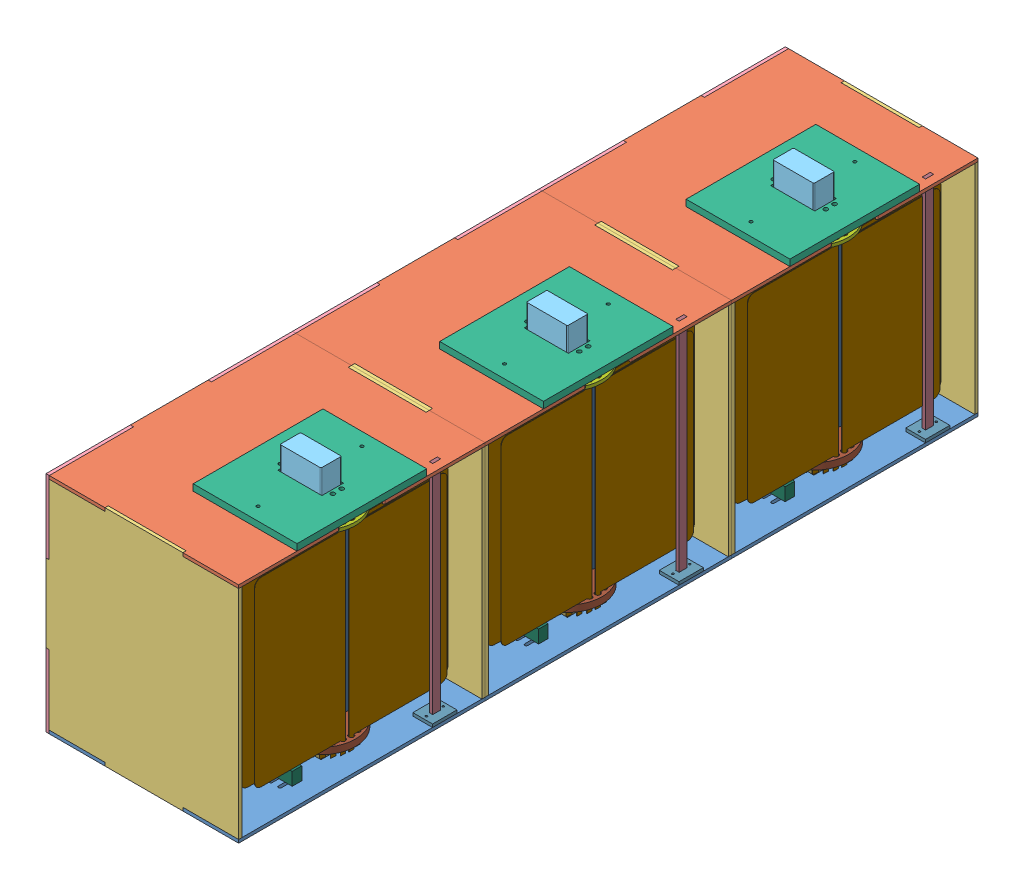
SolidWorks assembly AllAssembly-v1-stacked, configuration Default. Lengths in mm.
Overall size (189.19 247.83 723.9).
132 component instances, 15 part files, 6 mates.
Components (placement in the parent):
- BasicFlipbook-1: BasicFlipbook [Default] at (-56.8677 536.304 -217.1524) size (189.19 247.83 241.3)
  - sidePanel-bearing-1: sidePanel-bearing [Default] at (77.8088 -538.0926 524.9276) size (188.59 3.17 241.3)
  - sidePanel-spindle-1: sidePanel-spindle [Default] at (77.8088 -322.1926 524.9276) size (188.59 3.17 241.3)
  - topPanel-1: topPanel [Default] at (170.5188 -428.5551 283.6276) x (0 -1 0) z (0 0 1) size (219.07 188.59 3.17)
  - topPanel-2: topPanel [Default] at (170.5188 -428.5551 521.7526) x (0 -1 0) z (0 0 1) size (219.07 188.59 3.17)
  - backPanel-1: backPanel [Default] at (77.8088 -538.0926 524.9276) x (0 1 0) z (0 0 1) size (219.07 3.17 241.3)
  - servo-1: servo [Default] at (213.1908 -290.2676 404.2776) x (1 0 0) z (0 -1 0) size (52.83 20.07 43.1)
  - sidePanel-motor-1: sidePanel-motor [Default] at (77.8088 -319.0176 524.9276) size (101.6 6.35 127)
  - FlipHubAssy_11_14_16-2: FlipHubAssy_11_14_16 [Default] at (223.2238 -424.2676 404.2776) x (0 1 0) z (0.343761 0 0.939057) size (212.25 171.9 216.35) (flexible)
    - Hub_11_16_16v1-3: Hub_11_16_16v1 [Kerf Removed] at (92.075 0 0) x (0 -0.836215 0.548402) z (1 0 0) size (67.6 67.6 3.17)
    - 4mmShaft-1: 4mmShaft [Default] at (-110.65 0 0) x (0 0.397838 0.917456) z (1 0 0) size (4 4 201.85)
    - flipcard-2: flipcard [Default] at (101.6 -15.2897 -21.654) x (-1 0 0) z (0 0.118273 0.992981) size (203.2 0.36 88.9)
    - flipcard-3: flipcard [Default] at (101.6 -20.7049 -16.8264) x (-1 0 0) z (0 0.229727 0.973255) size (203.2 0.36 88.9)
    - flipcard-4: flipcard [Default] at (101.6 -24.7798 -10.679) x (-1 0 0) z (0 0.290896 0.956755) size (203.2 0.36 88.9)
    - flipcard-5: flipcard [Default] at (101.6 -27.1726 -3.6323) x (-1 0 0) z (0 0.324243 0.945974) size (203.2 0.36 88.9)
    - flipcard-6: flipcard [Default] at (101.6 -27.6554 3.8125) x (-1 0 0) z (0 0.355007 0.934864) size (203.2 0.36 88.9)
    - flipcard-7: flipcard [Default] at (101.6 6.9617 25.991) x (-1 0 0) z (0 -0.804275 -0.594258) size (203.2 0.36 88.9)
    - flipcard-8: flipcard [Default] at (101.6 13.6608 22.8217) x (-1 0 0) z (0 -0.829103 -0.559096) size (203.2 0.36 88.9)
    - flipcard-9: flipcard [Default] at (101.6 12.4258 -23.2935) x (-1 0 0) z (0 -0.27854 0.960425) size (203.2 0.36 88.9)
    - flipcard-10: flipcard [Default] at (101.6 19.1668 18.301) x (-1 0 0) z (0 -0.912348 -0.409415) size (203.2 0.36 88.9)
    - flipcard-11: flipcard [Default] at (101.6 25.8239 6.5692) x (-1 0 0) z (0 -0.973268 0.229671) size (203.2 0.36 88.9)
    - flipcard-12: flipcard [Default] at (101.6 -7.402 26.2839) x (-1 0 0) z (0 -0.588891 -0.808212) size (203.2 0.36 88.9)
    - flipcard-13: flipcard [Default] at (101.6 23.2571 13.1974) x (-1 0 0) z (0 -0.999195 0.040112) size (203.2 0.36 88.9)
    - flipcard-14: flipcard [Default] at (101.6 -0.029 26.9321) x (-1 0 0) z (0 -0.634806 -0.772672) size (203.2 0.36 88.9)
    - flipcard-15: flipcard [Default] at (101.6 -14.3329 23.6973) x (-1 0 0) z (0 -0.524162 -0.851618) size (203.2 0.36 88.9)
    - flipcard-16: flipcard [Default] at (101.6 25.5857 -7.2828) x (-1 0 0) z (0 -0.75236 0.658752) size (203.2 0.36 88.9)
    - flipcard-17: flipcard [Default] at (101.6 -20.2143 19.2851) x (-1 0 0) z (0 -0.387069 -0.922051) size (203.2 0.36 88.9)
    - flipcard-18: flipcard [Default] at (101.6 -26.2822 11.1902) x (-1 0 0) z (0 0.343761 0.939057) size (203.2 0.36 88.9)
    - flipcard-19: flipcard [Default] at (101.6 26.6468 -0.3343) x (-1 0 0) z (0 -0.879712 0.475507) size (203.2 0.36 88.9)
    - flipcard-20: flipcard [Default] at (101.6 -25.0081 13.5575) x (-1 0 0) z (0 -0.343761 -0.939057) size (203.2 0.36 88.9)
    - flipcard-21: flipcard [Default] at (101.6 22.7931 -13.6775) x (-1 0 0) z (0 -0.570443 0.821337) size (203.2 0.36 88.9)
    - flipcard-22: flipcard [Default] at (101.6 5.6236 -25.7226) x (-1 0 0) z (0 -0.165302 0.986243) size (203.2 0.36 88.9)
    - flipcard-23: flipcard [Default] at (101.6 -1.5593 -26.2681) x (-1 0 0) z (0 -0.043757 0.999042) size (203.2 0.36 88.9)
    - flipcard-24: flipcard [Default] at (101.6 18.5239 -19.098) x (-1 0 0) z (0 -0.319136 0.947709) size (203.2 0.36 88.9)
    - flipcard-26: flipcard [Default] at (101.6 -8.628 -24.8962) x (-1 0 0) z (0 0.08016 0.996782) size (203.2 0.36 88.9)
    - CenterSupport-2: CenterSupport [After Cut Kerf Removed] at (0 3.7916 3.0025) x (1 0 0) z (0 -0.836215 0.548402) size (190.5 19.05 3.05)
    - CenterSupport-3: CenterSupport [After Cut Kerf Removed] at (0 -3.0025 3.7916) x (1 0 0) z (0 -0.548402 -0.836215) size (190.5 19.05 3.05)
    - CenterSupport-4: CenterSupport [After Cut Kerf Removed] at (0 -3.7916 -3.0025) x (1 0 0) z (0 0.836215 -0.548402) size (190.5 19.05 3.05)
    - CenterSupport-5: CenterSupport [After Cut Kerf Removed] at (0 3.0025 -3.7916) x (1 0 0) z (0 0.548402 0.836215) size (190.5 19.05 3.05)
    - Hub_11_16_16v1-thicker-3: Hub_11_16_16v1-thicker [Kerf Removed] at (-95.25 0 0) x (0 -0.548402 -0.836215) z (1 0 0) size (67.6 72.68 6.35)
    - bearingSleeve-nut-1: bearingSleeve-nut [Default] at (-109.05 0 0) x (0 -0.939057 0.343761) z (-1 0 0) size (25.4 25.4 6.95)
  - stopper-2: stopper [Default] at (255.3548 -538.0926 327.0616) x (0 1 0) z (-1 0 0) size (219.07 7.87 3.3)
  - stopperSupport-1: stopperSupport [Default] at (243.9268 -531.9176 311.1876) x (1 0 0) z (0 -1 0) size (19.3 23.87 3)
  - switchSupport-1: switchSupport [Default] at (224.5478 -534.9176 453.6616) x (1 0 0) z (0 1 0) size (19.84 9.4 12.7)
- BasicFlipbook-2: BasicFlipbook [Default] at (-56.8677 536.304 -458.4524) size (189.19 247.83 241.3)
  - sidePanel-bearing-1: sidePanel-bearing [Default] at (77.8088 -538.0926 524.9276) size (188.59 3.17 241.3)
  - sidePanel-spindle-1: sidePanel-spindle [Default] at (77.8088 -322.1926 524.9276) size (188.59 3.17 241.3)
  - topPanel-1: topPanel [Default] at (170.5188 -428.5551 283.6276) x (0 -1 0) z (0 0 1) size (219.07 188.59 3.17)
  - topPanel-2: topPanel [Default] at (170.5188 -428.5551 521.7526) x (0 -1 0) z (0 0 1) size (219.07 188.59 3.17)
  - backPanel-1: backPanel [Default] at (77.8088 -538.0926 524.9276) x (0 1 0) z (0 0 1) size (219.07 3.17 241.3)
  - servo-1: servo [Default] at (213.1908 -290.2676 404.2776) x (1 0 0) z (0 -1 0) size (52.83 20.07 43.1)
  - sidePanel-motor-1: sidePanel-motor [Default] at (77.8088 -319.0176 524.9276) size (101.6 6.35 127)
  - FlipHubAssy_11_14_16-2: FlipHubAssy_11_14_16 [Default] at (223.2238 -424.2676 404.2776) x (0 1 0) z (0.343761 0 0.939057) size (212.25 171.9 216.35) (flexible)
    - Hub_11_16_16v1-3: Hub_11_16_16v1 [Kerf Removed] at (92.075 0 0) x (0 -0.836215 0.548402) z (1 0 0) size (67.6 67.6 3.17)
    - 4mmShaft-1: 4mmShaft [Default] at (-110.65 0 0) x (0 0.397838 0.917456) z (1 0 0) size (4 4 201.85)
    - flipcard-2: flipcard [Default] at (101.6 -15.2897 -21.654) x (-1 0 0) z (0 0.118273 0.992981) size (203.2 0.36 88.9)
    - flipcard-3: flipcard [Default] at (101.6 -20.7049 -16.8264) x (-1 0 0) z (0 0.229727 0.973255) size (203.2 0.36 88.9)
    - flipcard-4: flipcard [Default] at (101.6 -24.7798 -10.679) x (-1 0 0) z (0 0.290896 0.956755) size (203.2 0.36 88.9)
    - flipcard-5: flipcard [Default] at (101.6 -27.1726 -3.6323) x (-1 0 0) z (0 0.324243 0.945974) size (203.2 0.36 88.9)
    - flipcard-6: flipcard [Default] at (101.6 -27.6554 3.8125) x (-1 0 0) z (0 0.355007 0.934864) size (203.2 0.36 88.9)
    - flipcard-7: flipcard [Default] at (101.6 6.9617 25.991) x (-1 0 0) z (0 -0.804275 -0.594258) size (203.2 0.36 88.9)
    - flipcard-8: flipcard [Default] at (101.6 13.6608 22.8217) x (-1 0 0) z (0 -0.829103 -0.559096) size (203.2 0.36 88.9)
    - flipcard-9: flipcard [Default] at (101.6 12.4258 -23.2935) x (-1 0 0) z (0 -0.27854 0.960425) size (203.2 0.36 88.9)
    - flipcard-10: flipcard [Default] at (101.6 19.1668 18.301) x (-1 0 0) z (0 -0.912348 -0.409415) size (203.2 0.36 88.9)
    - flipcard-11: flipcard [Default] at (101.6 25.8239 6.5692) x (-1 0 0) z (0 -0.973268 0.229671) size (203.2 0.36 88.9)
    - flipcard-12: flipcard [Default] at (101.6 -7.402 26.2839) x (-1 0 0) z (0 -0.588891 -0.808212) size (203.2 0.36 88.9)
    - flipcard-13: flipcard [Default] at (101.6 23.2571 13.1974) x (-1 0 0) z (0 -0.999195 0.040112) size (203.2 0.36 88.9)
    - flipcard-14: flipcard [Default] at (101.6 -0.029 26.9321) x (-1 0 0) z (0 -0.634806 -0.772672) size (203.2 0.36 88.9)
    - flipcard-15: flipcard [Default] at (101.6 -14.3329 23.6973) x (-1 0 0) z (0 -0.524162 -0.851618) size (203.2 0.36 88.9)
    - flipcard-16: flipcard [Default] at (101.6 25.5857 -7.2828) x (-1 0 0) z (0 -0.75236 0.658752) size (203.2 0.36 88.9)
    - flipcard-17: flipcard [Default] at (101.6 -20.2143 19.2851) x (-1 0 0) z (0 -0.387069 -0.922051) size (203.2 0.36 88.9)
    - flipcard-18: flipcard [Default] at (101.6 -26.2822 11.1902) x (-1 0 0) z (0 0.343761 0.939057) size (203.2 0.36 88.9)
    - flipcard-19: flipcard [Default] at (101.6 26.6468 -0.3343) x (-1 0 0) z (0 -0.879712 0.475507) size (203.2 0.36 88.9)
    - flipcard-20: flipcard [Default] at (101.6 -25.0081 13.5575) x (-1 0 0) z (0 -0.343761 -0.939057) size (203.2 0.36 88.9)
    - flipcard-21: flipcard [Default] at (101.6 22.7931 -13.6775) x (-1 0 0) z (0 -0.570443 0.821337) size (203.2 0.36 88.9)
    - flipcard-22: flipcard [Default] at (101.6 5.6236 -25.7226) x (-1 0 0) z (0 -0.165302 0.986243) size (203.2 0.36 88.9)
    - flipcard-23: flipcard [Default] at (101.6 -1.5593 -26.2681) x (-1 0 0) z (0 -0.043757 0.999042) size (203.2 0.36 88.9)
    - flipcard-24: flipcard [Default] at (101.6 18.5239 -19.098) x (-1 0 0) z (0 -0.319136 0.947709) size (203.2 0.36 88.9)
    - flipcard-26: flipcard [Default] at (101.6 -8.628 -24.8962) x (-1 0 0) z (0 0.08016 0.996782) size (203.2 0.36 88.9)
    - CenterSupport-2: CenterSupport [After Cut Kerf Removed] at (0 3.7916 3.0025) x (1 0 0) z (0 -0.836215 0.548402) size (190.5 19.05 3.05)
    - CenterSupport-3: CenterSupport [After Cut Kerf Removed] at (0 -3.0025 3.7916) x (1 0 0) z (0 -0.548402 -0.836215) size (190.5 19.05 3.05)
    - CenterSupport-4: CenterSupport [After Cut Kerf Removed] at (0 -3.7916 -3.0025) x (1 0 0) z (0 0.836215 -0.548402) size (190.5 19.05 3.05)
    - CenterSupport-5: CenterSupport [After Cut Kerf Removed] at (0 3.0025 -3.7916) x (1 0 0) z (0 0.548402 0.836215) size (190.5 19.05 3.05)
    - Hub_11_16_16v1-thicker-3: Hub_11_16_16v1-thicker [Kerf Removed] at (-95.25 0 0) x (0 -0.548402 -0.836215) z (1 0 0) size (67.6 72.68 6.35)
    - bearingSleeve-nut-1: bearingSleeve-nut [Default] at (-109.05 0 0) x (0 -0.939057 0.343761) z (-1 0 0) size (25.4 25.4 6.95)
  - stopper-2: stopper [Default] at (255.3548 -538.0926 327.0616) x (0 1 0) z (-1 0 0) size (219.07 7.87 3.3)
  - stopperSupport-1: stopperSupport [Default] at (243.9268 -531.9176 311.1876) x (1 0 0) z (0 -1 0) size (19.3 23.87 3)
  - switchSupport-1: switchSupport [Default] at (224.5478 -534.9176 453.6616) x (1 0 0) z (0 1 0) size (19.84 9.4 12.7)
- BasicFlipbook-3: BasicFlipbook [Default] at (-56.8677 536.304 -699.7524) size (189.19 247.83 241.3)
  - sidePanel-bearing-1: sidePanel-bearing [Default] at (77.8088 -538.0926 524.9276) size (188.59 3.17 241.3)
  - sidePanel-spindle-1: sidePanel-spindle [Default] at (77.8088 -322.1926 524.9276) size (188.59 3.17 241.3)
  - topPanel-1: topPanel [Default] at (170.5188 -428.5551 283.6276) x (0 -1 0) z (0 0 1) size (219.07 188.59 3.17)
  - topPanel-2: topPanel [Default] at (170.5188 -428.5551 521.7526) x (0 -1 0) z (0 0 1) size (219.07 188.59 3.17)
  - backPanel-1: backPanel [Default] at (77.8088 -538.0926 524.9276) x (0 1 0) z (0 0 1) size (219.07 3.17 241.3)
  - servo-1: servo [Default] at (213.1908 -290.2676 404.2776) x (1 0 0) z (0 -1 0) size (52.83 20.07 43.1)
  - sidePanel-motor-1: sidePanel-motor [Default] at (77.8088 -319.0176 524.9276) size (101.6 6.35 127)
  - FlipHubAssy_11_14_16-2: FlipHubAssy_11_14_16 [Default] at (223.2238 -424.2676 404.2776) x (0 1 0) z (0.343761 0 0.939057) size (212.25 171.9 216.35) (flexible)
    - Hub_11_16_16v1-3: Hub_11_16_16v1 [Kerf Removed] at (92.075 0 0) x (0 -0.836215 0.548402) z (1 0 0) size (67.6 67.6 3.17)
    - 4mmShaft-1: 4mmShaft [Default] at (-110.65 0 0) x (0 0.397838 0.917456) z (1 0 0) size (4 4 201.85)
    - flipcard-2: flipcard [Default] at (101.6 -15.2897 -21.654) x (-1 0 0) z (0 0.118273 0.992981) size (203.2 0.36 88.9)
    - flipcard-3: flipcard [Default] at (101.6 -20.7049 -16.8264) x (-1 0 0) z (0 0.229727 0.973255) size (203.2 0.36 88.9)
    - flipcard-4: flipcard [Default] at (101.6 -24.7798 -10.679) x (-1 0 0) z (0 0.290896 0.956755) size (203.2 0.36 88.9)
    - flipcard-5: flipcard [Default] at (101.6 -27.1726 -3.6323) x (-1 0 0) z (0 0.324243 0.945974) size (203.2 0.36 88.9)
    - flipcard-6: flipcard [Default] at (101.6 -27.6554 3.8125) x (-1 0 0) z (0 0.355007 0.934864) size (203.2 0.36 88.9)
    - flipcard-7: flipcard [Default] at (101.6 6.9617 25.991) x (-1 0 0) z (0 -0.804275 -0.594258) size (203.2 0.36 88.9)
    - flipcard-8: flipcard [Default] at (101.6 13.6608 22.8217) x (-1 0 0) z (0 -0.829103 -0.559096) size (203.2 0.36 88.9)
    - flipcard-9: flipcard [Default] at (101.6 12.4258 -23.2935) x (-1 0 0) z (0 -0.27854 0.960425) size (203.2 0.36 88.9)
    - flipcard-10: flipcard [Default] at (101.6 19.1668 18.301) x (-1 0 0) z (0 -0.912348 -0.409415) size (203.2 0.36 88.9)
    - flipcard-11: flipcard [Default] at (101.6 25.8239 6.5692) x (-1 0 0) z (0 -0.973268 0.229671) size (203.2 0.36 88.9)
    - flipcard-12: flipcard [Default] at (101.6 -7.402 26.2839) x (-1 0 0) z (0 -0.588891 -0.808212) size (203.2 0.36 88.9)
    - flipcard-13: flipcard [Default] at (101.6 23.2571 13.1974) x (-1 0 0) z (0 -0.999195 0.040112) size (203.2 0.36 88.9)
    - flipcard-14: flipcard [Default] at (101.6 -0.029 26.9321) x (-1 0 0) z (0 -0.634806 -0.772672) size (203.2 0.36 88.9)
    - flipcard-15: flipcard [Default] at (101.6 -14.3329 23.6973) x (-1 0 0) z (0 -0.524162 -0.851618) size (203.2 0.36 88.9)
    - flipcard-16: flipcard [Default] at (101.6 25.5857 -7.2828) x (-1 0 0) z (0 -0.75236 0.658752) size (203.2 0.36 88.9)
    - flipcard-17: flipcard [Default] at (101.6 -20.2143 19.2851) x (-1 0 0) z (0 -0.387069 -0.922051) size (203.2 0.36 88.9)
    - flipcard-18: flipcard [Default] at (101.6 -26.2822 11.1902) x (-1 0 0) z (0 0.343761 0.939057) size (203.2 0.36 88.9)
    - flipcard-19: flipcard [Default] at (101.6 26.6468 -0.3343) x (-1 0 0) z (0 -0.879712 0.475507) size (203.2 0.36 88.9)
    - flipcard-20: flipcard [Default] at (101.6 -25.0081 13.5575) x (-1 0 0) z (0 -0.343761 -0.939057) size (203.2 0.36 88.9)
    - flipcard-21: flipcard [Default] at (101.6 22.7931 -13.6775) x (-1 0 0) z (0 -0.570443 0.821337) size (203.2 0.36 88.9)
    - flipcard-22: flipcard [Default] at (101.6 5.6236 -25.7226) x (-1 0 0) z (0 -0.165302 0.986243) size (203.2 0.36 88.9)
    - flipcard-23: flipcard [Default] at (101.6 -1.5593 -26.2681) x (-1 0 0) z (0 -0.043757 0.999042) size (203.2 0.36 88.9)
    - flipcard-24: flipcard [Default] at (101.6 18.5239 -19.098) x (-1 0 0) z (0 -0.319136 0.947709) size (203.2 0.36 88.9)
    - flipcard-26: flipcard [Default] at (101.6 -8.628 -24.8962) x (-1 0 0) z (0 0.08016 0.996782) size (203.2 0.36 88.9)
    - CenterSupport-2: CenterSupport [After Cut Kerf Removed] at (0 3.7916 3.0025) x (1 0 0) z (0 -0.836215 0.548402) size (190.5 19.05 3.05)
    - CenterSupport-3: CenterSupport [After Cut Kerf Removed] at (0 -3.0025 3.7916) x (1 0 0) z (0 -0.548402 -0.836215) size (190.5 19.05 3.05)
    - CenterSupport-4: CenterSupport [After Cut Kerf Removed] at (0 -3.7916 -3.0025) x (1 0 0) z (0 0.836215 -0.548402) size (190.5 19.05 3.05)
    - CenterSupport-5: CenterSupport [After Cut Kerf Removed] at (0 3.0025 -3.7916) x (1 0 0) z (0 0.548402 0.836215) size (190.5 19.05 3.05)
    - Hub_11_16_16v1-thicker-3: Hub_11_16_16v1-thicker [Kerf Removed] at (-95.25 0 0) x (0 -0.548402 -0.836215) z (1 0 0) size (67.6 72.68 6.35)
    - bearingSleeve-nut-1: bearingSleeve-nut [Default] at (-109.05 0 0) x (0 -0.939057 0.343761) z (-1 0 0) size (25.4 25.4 6.95)
  - stopper-2: stopper [Default] at (255.3548 -538.0926 327.0616) x (0 1 0) z (-1 0 0) size (219.07 7.87 3.3)
  - stopperSupport-1: stopperSupport [Default] at (243.9268 -531.9176 311.1876) x (1 0 0) z (0 -1 0) size (19.3 23.87 3)
  - switchSupport-1: switchSupport [Default] at (224.5478 -534.9176 453.6616) x (1 0 0) z (0 1 0) size (19.84 9.4 12.7)
Mates (geometry in assembly coordinates):
- Coincident1: coincident anti-aligned: plane of BasicFlipbook-1/topPanel-1 through (113.6511 107.7489 66.4752) normal (0 0 -1); plane of BasicFlipbook-2/topPanel-2 through (113.6511 107.7489 66.4752) normal (0 0 1)
- Coincident2: coincident aligned: plane of BasicFlipbook-1/topPanel-1 through (206.3611 214.1114 69.6502) normal (1 0 0); plane of BasicFlipbook-2/topPanel-2 through (206.3611 214.1114 66.4752) normal (1 0 0)
- Coincident3: coincident aligned: plane of BasicFlipbook-1/sidePanel-bearing-1 through (20.9411 -1.7886 307.7752) normal (0 -1 0); plane of BasicFlipbook-2/sidePanel-bearing-1 through (20.9411 -1.7886 66.4752) normal (0 -1 0)
- Coincident4: coincident anti-aligned: plane of BasicFlipbook-2/topPanel-1 through (113.6511 107.7489 -174.8248) normal (0 0 -1); plane of BasicFlipbook-3/topPanel-2 through (113.6511 107.7489 -174.8248) normal (0 0 1)
- Coincident5: coincident aligned: plane of BasicFlipbook-2/sidePanel-bearing-1 through (20.9411 -1.7886 66.4752) normal (0 -1 0); plane of BasicFlipbook-3/sidePanel-bearing-1 through (20.9411 -1.7886 -174.8248) normal (0 -1 0)
- Coincident6: coincident aligned: plane of BasicFlipbook-2/topPanel-1 through (206.3611 214.1114 -171.6498) normal (1 0 0); plane of BasicFlipbook-3/topPanel-2 through (206.3611 214.1114 -174.8248) normal (1 0 0)
